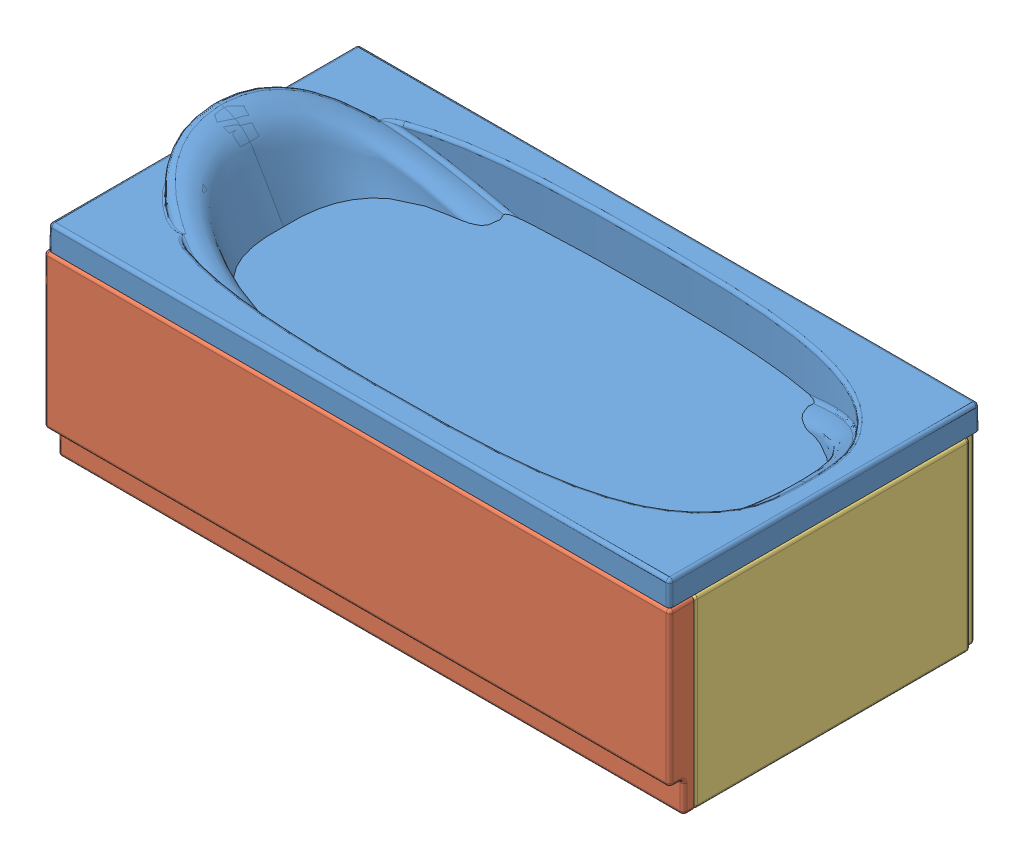
SolidWorks assembly Country 1801125, configuration По умолчанию. Lengths in mm.
Overall size (1810 718.62 956.2).
4 component instances, 3 part files, 9 mates.
Components (placement in the parent):
- Модель 1800x900-1: Модель 1800x900 [По умолчанию] at (0.2851 -237.1701 -23.1345) size (1798.91 654.49 956.2)
- Панель 1800-1: Панель 1800 [По умолчанию] at (905.2851 -397.1701 366.3198) x (-1 0 0) z (0 0 -1) size (1810 550 70)
- Панель боковая 850-1: Панель боковая 850 [По умолчанию] at (878.2851 -117.1701 -38.6802) size (27 560 850)
- Панель боковая 850-2: Панель боковая 850 [По умолчанию] at (-877.7149 -117.1701 -38.6802) x (-1 0 0) z (0 0 -1) size (27 560 850)
Mates (geometry in assembly coordinates):
- Ширина1: width anti-aligned: plane of Модель 1800x900-1 through (-905.7149 -237.1701 -479.1345) normal (-0.999848 0.017452 0); plane of Модель 1800x900-1 through (906.2851 -237.1701 -479.1345) normal (0.999848 0.017452 0); plane of Панель 1800-1 through (905.2851 -397.1701 366.3198) normal (1 0 0); plane of Панель 1800-1 through (-904.7149 -397.1701 366.3198) normal (-1 0 0)
- Расстояние2: distance = 5 mm: line of Модель 1800x900-1 through (889.741 137.8299 426.3198) axis (-1 0 0); plane of Панель 1800-1 through (-904.7149 152.8299 431.3198) normal (0 0 1)
- Касательный1: tangent anti-aligned: plane of Модель 1800x900-1 through (932.6034 137.8299 -505.4528) normal (0 -1 0); cylinder of Панель 1800-1 through (-904.7149 127.8299 421.3198) axis (1 0 0) radius 10
- Совпадение12: coincident anti-aligned: plane of Панель 1800-1 through (875.2851 -297.1701 361.3198) normal (0 0 -1); line of Панель боковая 850-1 through (895.2851 -387.1701 361.3198) axis (0 1 0)
- Совпадение14: coincident aligned: plane of Панель 1800-1 through (905.2851 -397.1701 366.3198) normal (1 0 0); plane of Панель боковая 850-1 through (905.2851 137.8299 -438.6802) normal (1 0 0)
- Совпадение15: coincident aligned: plane of Панель 1800-1 through (-904.7149 -397.1701 391.3198) normal (0 -1 0); plane of Панель боковая 850-1 through (893.2851 -397.1701 -463.6802) normal (0 -1 0)
- Совпадение16: coincident aligned: plane of Панель боковая 850-2 through (-904.7149 137.8299 361.3198) normal (-1 0 0); plane of Панель 1800-1 through (-904.7149 -397.1701 366.3198) normal (-1 0 0)
- Совпадение17: coincident: plane of Панель 1800-1 through (875.2851 -297.1701 361.3198) normal (0 0 -1); line of Панель боковая 850-2 through (-894.7149 127.8299 361.3198) axis (0 -1 0)
- Совпадение18: coincident aligned: plane of Панель 1800-1 through (-904.7149 -397.1701 391.3198) normal (0 -1 0); plane of Панель боковая 850-2 through (-892.7149 -397.1701 386.3198) normal (0 -1 0)
